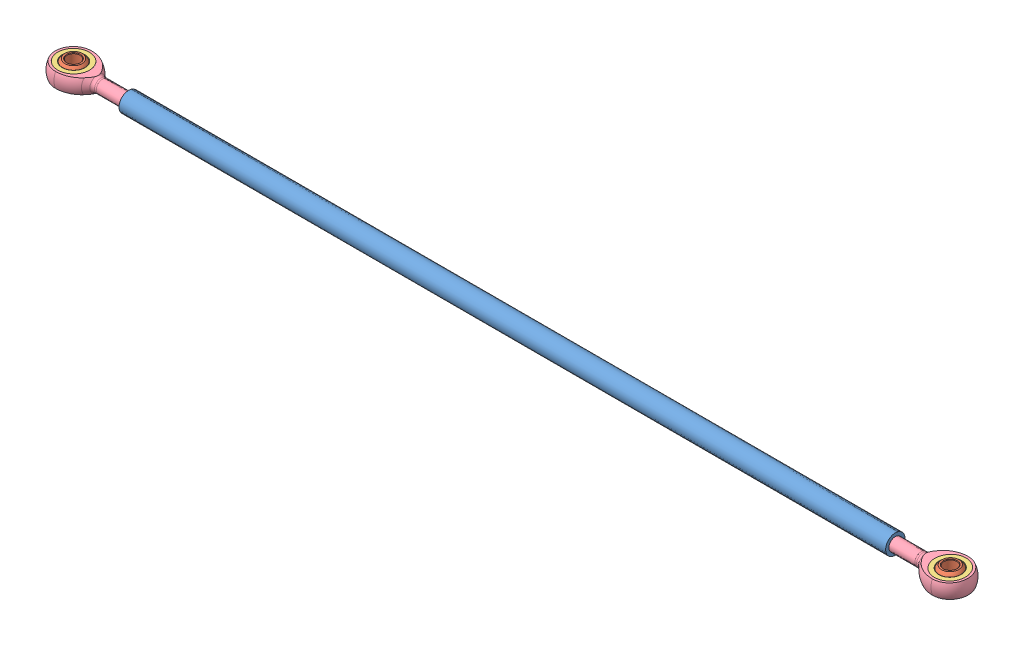
SolidWorks assembly Rear Toe Rod, configuration Default. Lengths in mm.
Overall size (449.27 21.09 22.84).
9 component instances, 4 part files, 4 mates.
Components (placement in the parent):
- Rear Toe Rod-1: Rear Toe Rod [Default<As Machined>] at (-71.6039 202.2538 295.7538) size (374.68 9.53 9.53)
- MM-4T Rod End-1: MM-4T Rod End [Default] at (-58.9224 201.713 296.8371) x (-0.027485 -0.013262 0.999534) z (-0.999534 0.01363 -0.027304) size (21.2 20.13 49.97) (flexible)
  - MM-4T Ball-1: MM-4T Ball [Default] at origin size (12.7 12.7 12.7)
  - MM-4T Sleeve-1: MM-4T Sleeve [Default] at (-1.0904 0.5261 0.0185) x (0.999384 0.022203 -0.027186) z (0.027485 -0.013262 0.999534) size (15.44 7.14 15.44)
  - MM-4T Housing-1: MM-4T Housing [Default] at (-1.0904 0.5261 0.0185) x (0.999384 0.022203 -0.027186) z (0.027485 -0.013262 0.999534) size (19.45 19.05 49.2)
- MM-4T Rod End-2: MM-4T Rod End [Default] at (290.39 201.742 294.6566) x (0.027485 0.013262 -0.999534) z (0.999534 0.012901 0.027656) size (21.2 20.13 49.97) (flexible)
  - MM-4T Ball-1: MM-4T Ball [Default] at origin size (12.7 12.7 12.7)
  - MM-4T Sleeve-1: MM-4T Sleeve [Default] at (-1.0904 0.5261 0.0185) x (0.999384 0.022203 -0.027186) z (0.027485 -0.013262 0.999534) size (15.44 7.14 15.44)
  - MM-4T Housing-1: MM-4T Housing [Default] at (-1.0904 0.5261 0.0185) x (0.999384 0.022203 -0.027186) z (0.027485 -0.013262 0.999534) size (19.45 19.05 49.2)
Mates (geometry in assembly coordinates):
- Concentric1: concentric anti-aligned: cylinder of Rear Toe Rod-1 through (303.0715 202.2538 295.7538) axis (-1 0 0) radius 4.7625; cylinder of MM-4T Rod End-1/MM-4T Housing-1 through (-71.8566 202.2538 295.7538) axis (1 0 0) radius 3.175
- Concentric2: concentric aligned: cylinder of Rear Toe Rod-1 through (303.0715 202.2538 295.7538) axis (-1 0 0) radius 4.7625; cylinder of ? through (303.3242 202.2538 295.7538) axis (-1 0 0) radius 3.175
- Coincident1: coincident: point of Rear Toe Rod-1; point of MM-4T Rod End-1/MM-4T Ball-1
- Coincident2: coincident: point of Rear Toe Rod-1; point of MM-4T Rod End-2/MM-4T Ball-1
